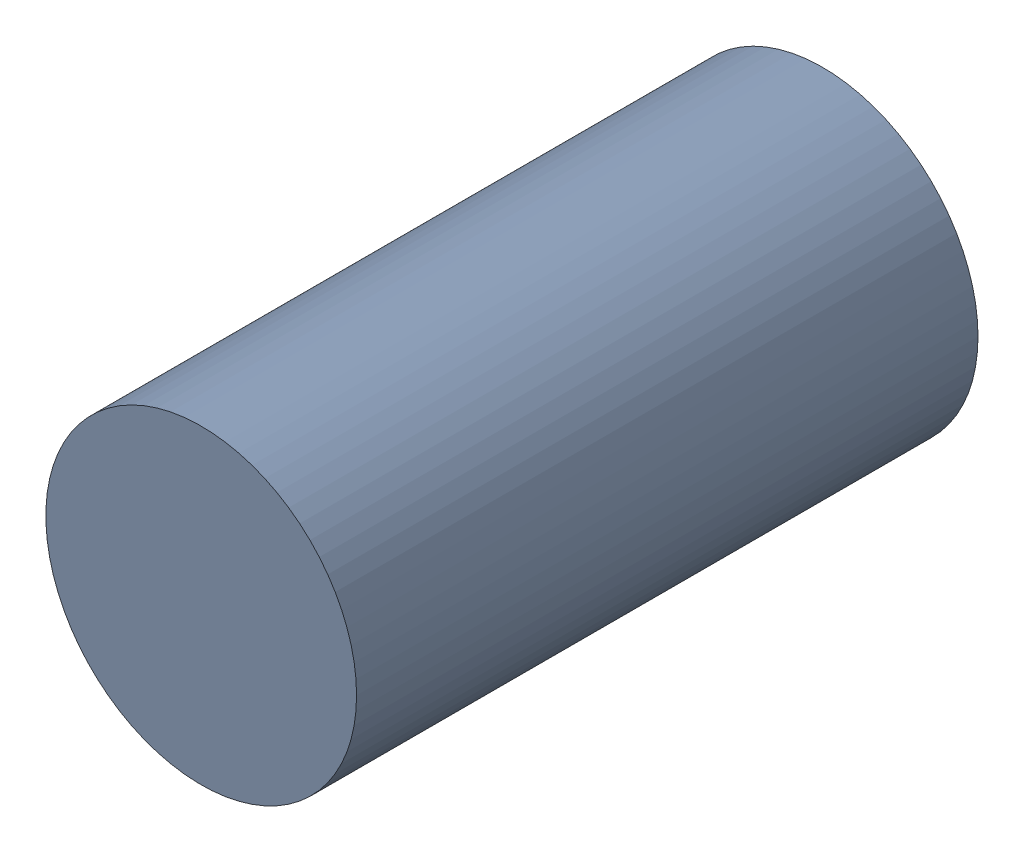
SolidWorks assembly MH11_1.step, configuration Default. Lengths in mm.
Overall size (1 1 2).
2 component instances, 1 part files, 0 mates.
Components (placement in the parent):
- 9228463120_1.step-11: 9228463120_1.step [Default] at (453.1614 297.4086 -1.5) size (1 1 2)
  - Cylinder_1.step-98: Cylinder_1.step [Default] at origin size (1 1 2)
